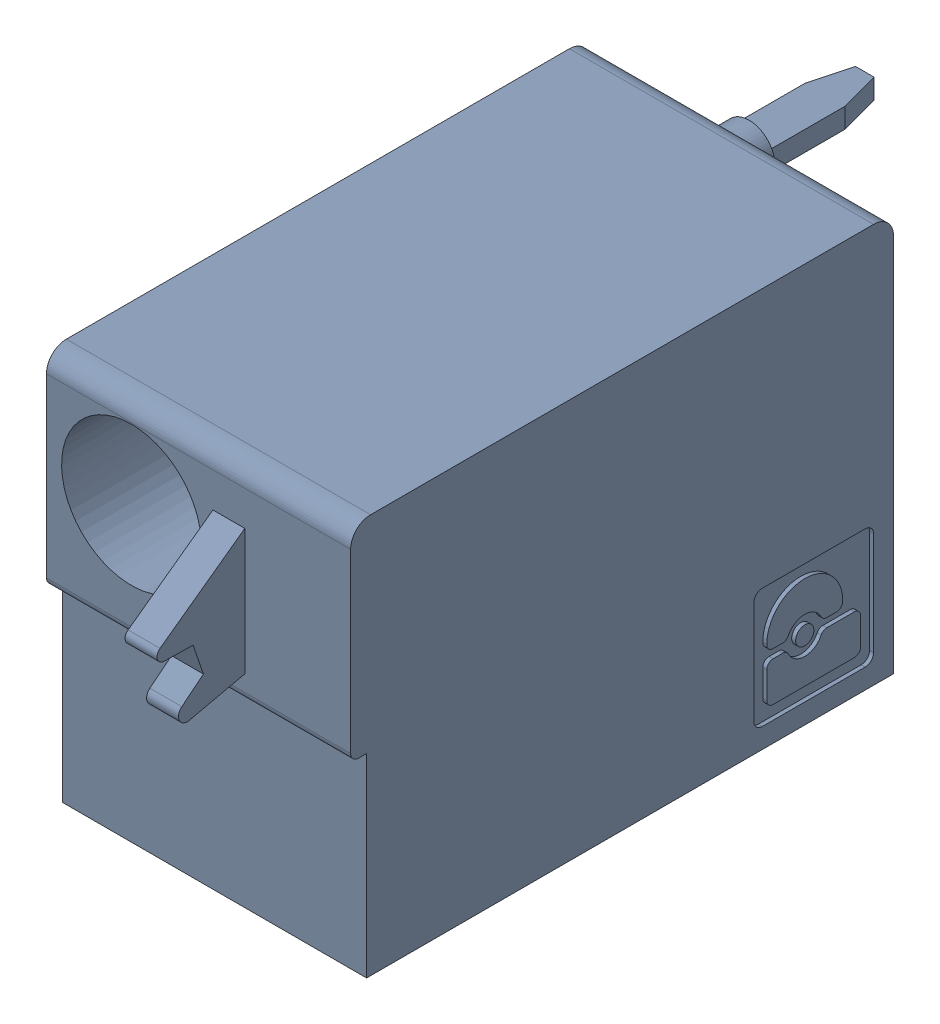
SolidWorks assembly J36, configuration Default. Lengths in mm.
Overall size (7.62 10 19.2).
2 component instances, 1 part files, 0 mates.
Components (placement in the parent):
- 1790487-1: 1790487 [Default] at (99.465 -5.67 -10.6) x (0 1 0) z (1 0 0) size (10 19.2 7.62)
  - ffkdsa1-v2-7.62-1: ffkdsa1-v2-7.62 [Default] at (-15.6914 -27.508 9.12) x (0 -1 0) z (0 0 1) size (19.2 10 7.62)
